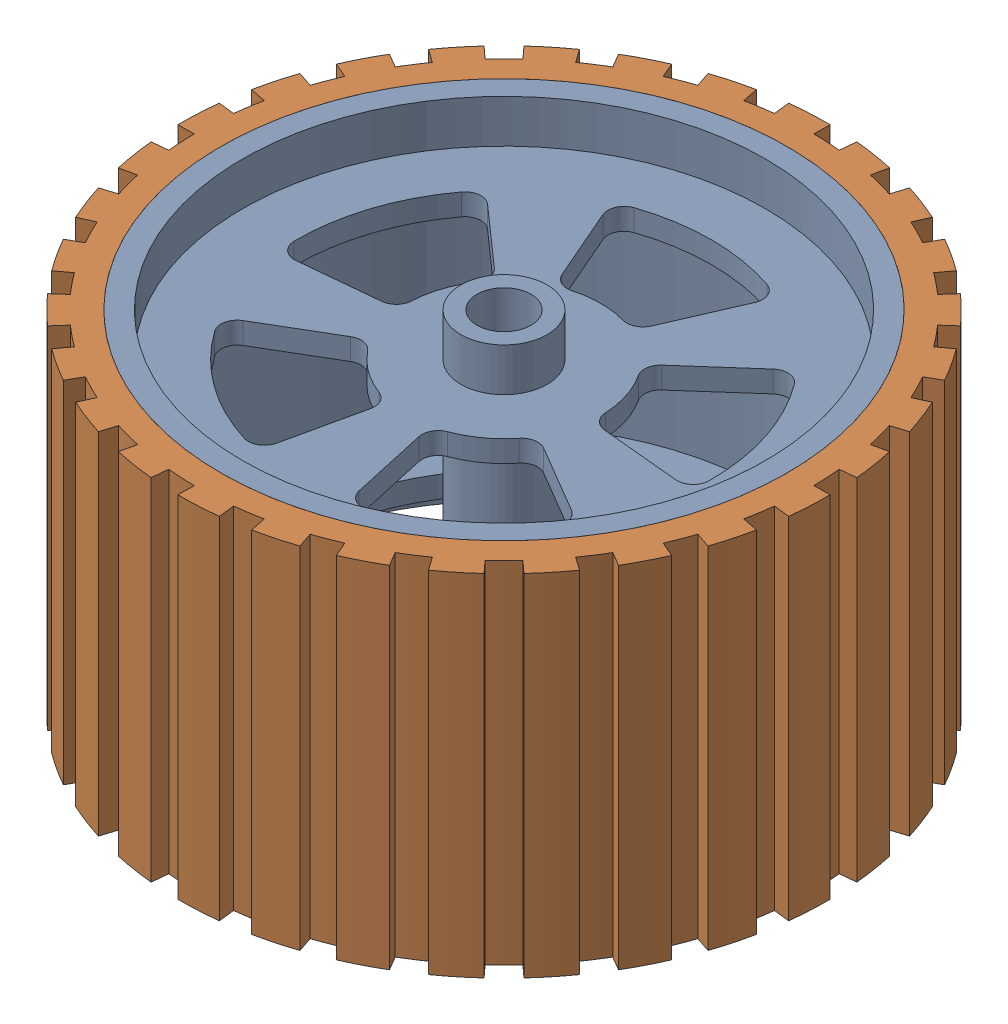
SolidWorks assembly wheel_rubber_assem, configuration Default. Lengths in mm.
Overall size (169.39 65 169.39).
2 component instances, 2 part files, 3 mates.
Components (placement in the parent):
- side_wheel rim-1: side_wheel rim [Default] at (-34.6242 -48.0043 32.6289) size (105 65 105)
- side_wheel_rubber-1: side_wheel_rubber [Default] at (-34.6242 -48.0043 32.6289) x (0.748956 0 0.66262) z (-0.66262 0 0.748956) size (120 65 120)
Mates (geometry in assembly coordinates):
- Concentric1: concentric aligned: cylinder of side_wheel rim-1 through (-34.6242 16.9957 32.6289) axis (0 -1 0) radius 52.5; cylinder of side_wheel_rubber-1 through (-34.6242 16.9957 32.6289) axis (0 -1 0) radius 52.5
- Coincident1: coincident aligned: circle of side_wheel rim-1; circle of side_wheel_rubber-1
- Parallel1: parallel aligned: plane of side_wheel rim-1 through (-34.6242 8.9957 32.6289) normal (0.66262 0 0.748956); plane of side_wheel_rubber-1 through (-34.6242 16.9957 32.6289) normal (0.66262 0 0.748956)
